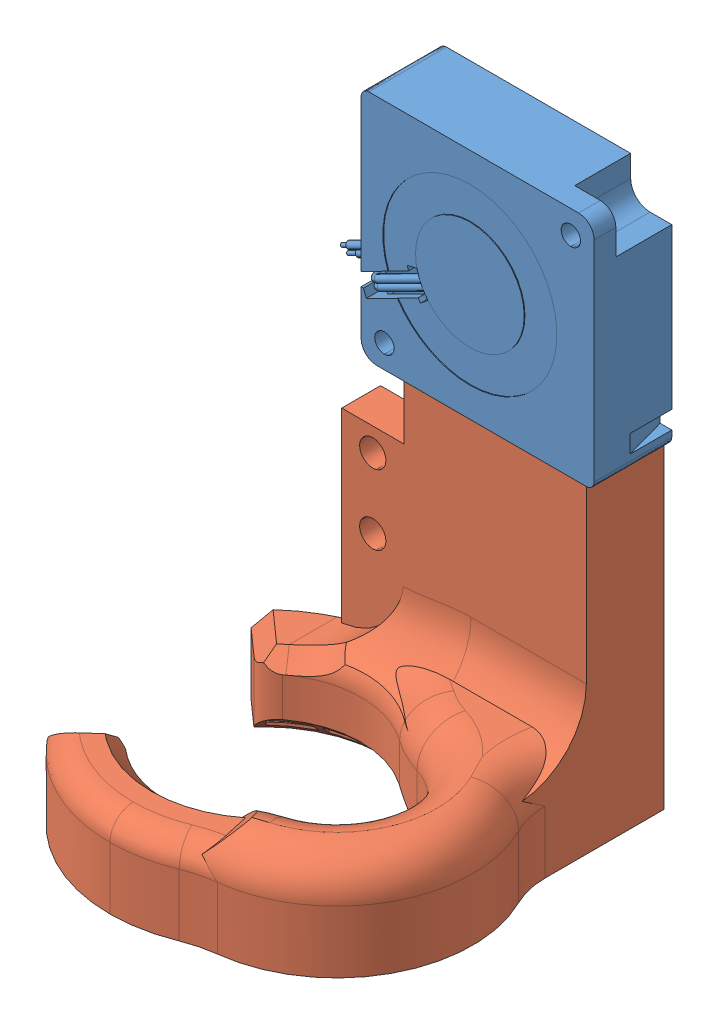
SolidWorks assembly FAN DUCT 6, configuration Default. Lengths in mm.
Overall size (47.51 71.05 47.35).
2 component instances, 2 part files, 3 mates.
Components (placement in the parent):
- Copy of Radial blower 30x10 v2^FAN DUCT 6-1: Copy of Radial blower 30x10 v2^FAN DUCT 6 [Default] at (10 29.9 -17.5) x (1 0 0) z (0 -1 0) size (40.51 10 30) (virtual)
- Copy of Fan Duct 6^FAN DUCT 6-1: Copy of Fan Duct 6^FAN DUCT 6 [Default] at (0 -26.1 0) x (-1 0 0) z (0 0 -1) size (41.68 41.05 47.35) (virtual)
Mates (geometry in assembly coordinates):
- Coincident1: coincident: plane of Copy of Radial blower 30x10 v2^FAN DUCT 6-1 through (10 29.9 -17.5) normal (0 0 1); plane of Copy of Fan Duct 6^FAN DUCT 6-1 through (400006.0057 3.9 -17.5) normal (0 0 1)
- Coincident2: coincident: plane of Copy of Radial blower 30x10 v2^FAN DUCT 6-1 through (23 38.6 -18.5) normal (-1 0 0); plane of Copy of Fan Duct 6^FAN DUCT 6-1 through (23 -16.1 0) normal (-1 0 0)
- Coincident3: coincident: plane of Copy of Radial blower 30x10 v2^FAN DUCT 6-1 through (25 14.9 -17.5) normal (0 -1 0); plane of Copy of Fan Duct 6^FAN DUCT 6-1 through (0 14.9 0) normal (0 1 0)
